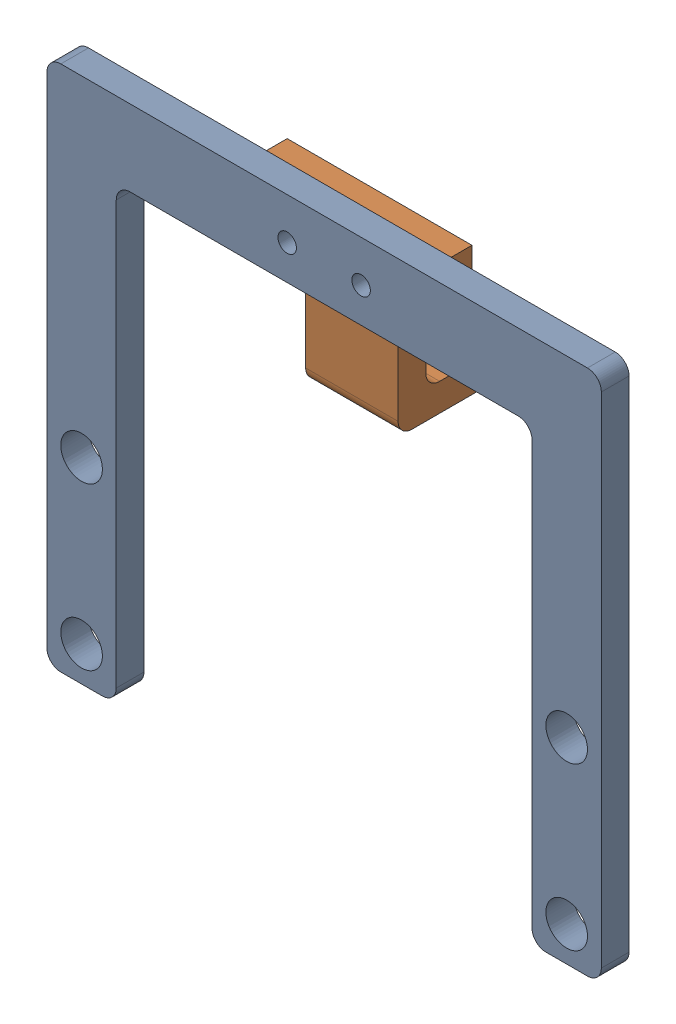
SolidWorks assembly Rear_Sensor_Assy, configuration Default. Lengths in mm.
Overall size (120 114 32).
2 component instances, 2 part files, 2 mates.
Components (placement in the parent):
- rear_sensor_mount-1: rear_sensor_mount [Default] at origin size (120 114 6)
- rear_sensor_holder-1: rear_sensor_holder [Default] at (0 0 -6) size (40 38 26)
Mates (geometry in assembly coordinates):
- Coincident1: coincident anti-aligned: plane of sensormount-1 through (57 -39.5 0) normal (0 0 -1); plane of sensormountextension-1 through (-15 50 0) normal (0 0 1)
- Concentric1: concentric aligned: cylinder of sensormount-1 through (8 62.5 6) axis (0 0 -1) radius 2; cylinder of sensormountextension-1 through (8 62.5 0) axis (0 0 -1) radius 2
